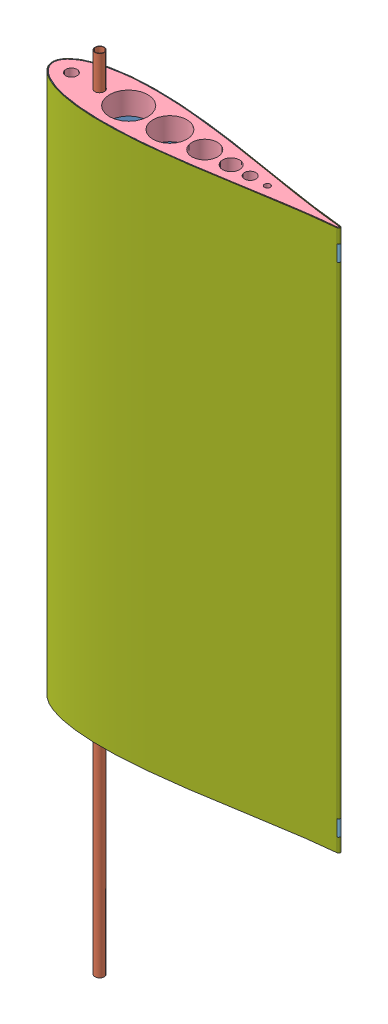
SolidWorks assembly MastBottom, configuration Default. Lengths in mm.
Overall size (684.25 1803.4 196.21).
12 component instances, 7 part files, 19 mates.
Components (placement in the parent):
- Leading edge model-1: Leading edge model [Default] at (515.5792 1096.0081 1180.2643) x (1 0 0) z (0 1 0) size (683.35 196.21 1258.66)
- Mast Bottom-1: Mast Bottom [Default] at (619.7192 -21.5919 1180.2643) size (21.08 1803.4 21.08)
- Base airfoil-1: Base airfoil [Default] at (515.5792 760.7281 1180.2643) x (1 0 0) z (0 -1 0) size (643.66 120.78 6.35)
- Base airfoil end cap-2: Base airfoil end cap [Default] at (515.5792 537.2081 1180.2643) x (1 0 0) z (0 -1 0) size (643.66 120.78 50.8)
- Base airfoil end cap-3: Base airfoil end cap [Default] at (515.5792 1705.6081 1180.2643) x (1 0 0) z (0 -1 0) size (643.66 120.78 50.8)
- End cap end cap-1: End cap end cap [Default] at (515.5792 1659.8881 1180.2643) x (1 0 0) z (0 -1 0) size (547.77 21 35.56)
- Carbon trailing edge-1: Carbon trailing edge [Default] at (1158.4163 527.6831 1180.2643) x (0 0 -1) z (1 0 0) size (2.54 1136.65 2.54)
- End cap end cap-2: End cap end cap [Default] at (515.5792 532.1281 1180.2643) x (1 0 0) z (0 1 0) size (547.77 21 35.56)
- Base airfoil-2: Base airfoil [Default] at (515.5792 984.2481 1180.2643) x (1 0 0) z (0 -1 0) size (643.66 120.78 6.35)
- Base airfoil-3: Base airfoil [Default] at (515.5792 1207.7681 1180.2643) x (1 0 0) z (0 -1 0) size (643.66 120.78 6.35)
- Base airfoil-4: Base airfoil [Default] at (515.5792 1431.2881 1180.2643) x (1 0 0) z (0 -1 0) size (643.66 120.78 6.35)
- PP Film Bottom-1: PP Film Bottom [Default] at (515.5792 486.4081 1180.2643) x (1 0 0) z (0 -1 0) size (648.6 125.32 1219.2)
Mates (geometry in assembly coordinates):
- Concentric4: concentric anti-aligned: cylinder of Mast Bottom-1 through (619.7192 1781.8081 1180.2643) axis (0 -1 0) radius 10.541; cylinder of Base airfoil-1 through (619.7192 754.3781 1180.2643) axis (0 1 0) radius 10.795
- Coincident7: coincident aligned: plane of Mast Bottom-1 through (619.7192 -21.5919 1180.2643) normal (0 0 1); plane of Base airfoil-1 through (515.5792 760.7281 1180.2643) normal (0 0 1)
- Concentric7: concentric anti-aligned: cylinder of Mast Bottom-1 through (619.7192 1781.8081 1180.2643) axis (0 -1 0) radius 10.541; cylinder of Base airfoil end cap-2 through (619.7192 486.4081 1180.2643) axis (0 1 0) radius 10.795
- Coincident10: coincident aligned: plane of Mast Bottom-1 through (619.7192 -21.5919 1180.2643) normal (0 0 1); plane of Base airfoil end cap-2 through (515.5792 537.2081 1180.2643) normal (0 0 1)
- Coincident11: coincident aligned: plane of Mast Bottom-1 through (619.7192 -21.5919 1180.2643) normal (0 0 1); plane of Base airfoil end cap-3 through (515.5792 1705.6081 1180.2643) normal (0 0 1)
- Distance2: distance = 508 mm aligned: plane of Mast Bottom-1 through (619.7192 -21.5919 1180.2643) normal (0 -1 0); plane of Base airfoil end cap-2 through (515.5792 486.4081 1180.2643) normal (0 -1 0)
- Distance9: distance = 76.2 mm aligned: plane of Base airfoil end cap-3 through (515.5792 1705.6081 1180.2643) normal (0 1 0); plane of Mast Bottom-1 through (619.7192 1781.8081 1180.2643) normal (0 1 0)
- Coincident74: coincident aligned: plane of Mast Bottom-1 through (619.7192 -21.5919 1180.2643) normal (0 0 1); plane of End cap end cap-1 through (515.5792 1659.8881 1180.2643) normal (0 0 1)
- Coincident75: coincident anti-aligned: plane of Mast Bottom-1 through (619.7192 -21.5919 1180.2643) normal (0 0 1); plane of End cap end cap-2 through (515.5792 532.1281 1180.2643) normal (0 0 -1)
- Coincident52: coincident anti-aligned: plane of Base airfoil end cap-2 through (515.5792 537.2081 1180.2643) normal (0 1 0); plane of End cap end cap-2 through (1059.6815 537.2081 1188.4214) normal (0 -1 0)
- Coincident118: coincident aligned: plane of Base airfoil end cap-2 through (515.5792 537.2081 1180.2643) normal (1 0 0); plane of Leading edge model-1 through (515.5792 1096.0081 1180.2643) normal (1 0 0)
- Coincident119: coincident aligned: plane of Base airfoil end cap-2 through (515.5792 486.4081 1180.2643) normal (0 -1 0); plane of Leading edge model-1 through (515.5792 486.4081 1180.2643) normal (0 -1 0)
- Coincident120: coincident anti-aligned: plane of Base airfoil end cap-2 through (515.5792 537.2081 1180.2643) normal (0 0 1); plane of Leading edge model-1 through (515.5792 1096.0081 1180.2643) normal (0 0 -1)
- Concentric21: concentric anti-aligned: cylinder of Base airfoil end cap-3 through (1158.4163 1654.8081 1180.2643) axis (0 1 0) radius 1.27; cylinder of Carbon trailing edge-1 through (1158.4163 1664.3331 1180.2643) axis (0 -1 0) radius 1.27
- Coincident54: coincident anti-aligned: plane of Base airfoil end cap-3 through (515.5792 1654.8081 1180.2643) normal (0 -1 0); plane of End cap end cap-1 through (1059.6815 1654.8081 1172.1072) normal (0 1 0)
- Distance11: distance = 223.52 mm anti-aligned: plane of Base airfoil-4 through (515.5792 1431.2881 1180.2643) normal (0 1 0); plane of Base airfoil end cap-3 through (515.5792 1654.8081 1180.2643) normal (0 -1 0)
- Concentric56: concentric aligned: cylinder of Carbon trailing edge-1 through (1158.4163 1664.3331 1180.2643) axis (0 -1 0) radius 1.27; cylinder of End cap end cap-1 through (1158.4163 1664.3331 1180.2643) axis (0 -1 0) radius 1.524
- Coincident53: coincident anti-aligned: plane of Carbon trailing edge-1 through (1158.4163 527.6831 1180.2643) normal (0 -1 0); plane of End cap end cap-2 through (1158.4163 527.6831 1180.2643) normal (0 1 0)
- Concentric55: concentric anti-aligned: cylinder of Carbon trailing edge-1 through (1158.4163 1664.3331 1180.2643) axis (0 -1 0) radius 1.27; cylinder of End cap end cap-2 through (1158.4163 527.6831 1180.2643) axis (0 1 0) radius 1.524
